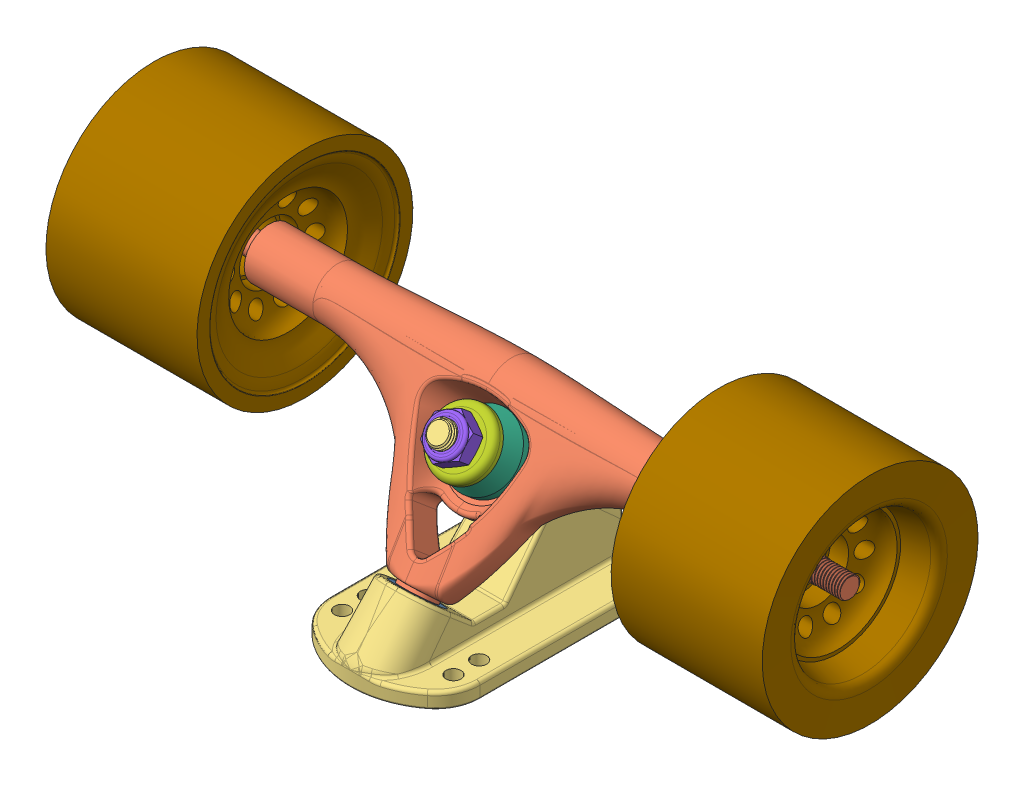
SolidWorks assembly Truck, configuration Default. Lengths in mm.
Overall size (265.5 107.22 102.66).
10 component instances, 9 part files, 22 mates.
Components (placement in the parent):
- Rubber Bushing-1: Rubber Bushing [Default] at (-27.686 9.105 71.5015) x (-0.125245 -0.637726 -0.760012) z (0 0.766044 -0.642788) size (17.78 17.78 15.24)
- Truck Black-1: Truck Black [Default] at (-27.686 18.8338 63.3381) x (1 0 0) z (0 -0.766044 0.642788) size (251.63 24.69 81.31)
- Truck Silver-1: Truck Silver [Default] at (-27.686 0 0) x (-1 0 0) z (0 0 -1) size (55.37 68.72 102.66)
- Large Washer-1: Large Washer [Default] at (-27.686 37.0748 22.445) x (1 0 0) z (0 -0.642788 -0.766044) size (29.97 29.97 4.65)
- Fat Bushing-1: Fat Bushing [Default] at (-27.686 38.3809 24.0016) x (0.983823 -0.137233 0.115152) z (-0.179144 -0.753652 0.632389) size (25.4 13.76 25.4)
- Small Bushing-1: Small Bushing [Default] at (-27.686 49.674 37.4601) x (0.221595 -0.747 0.626807) z (0 -0.642788 -0.766044) size (25.4 25.4 13.33)
- Small Washer-1: Small Washer [Default] at (-27.686 59.5517 49.2319) x (0.99468 -0.07891 0.066213) z (0 0.642788 0.766044) size (23.24 23.24 4.15)
- 3_8 nut-1: 3_8 nut [94945A218] at (-27.686 59.5517 49.2319) x (1 0 0) z (0 -0.766044 0.642788) size (14.29 7.02 16.5)
- Kegel 80mm longboard wheel-1: Kegel 80mm longboard wheel [Default] at (-123.0988 64.6541 29.035) x (0 -0.998139 0.06098) z (0 0.06098 0.998139) size (80 56 80)
- Kegel 80mm longboard wheel-2: Kegel 80mm longboard wheel [Default] at (67.7268 64.6541 29.035) x (0 -0.998139 0.06098) z (0 -0.06098 -0.998139) size (80 56 80)
Mates (geometry in assembly coordinates):
- Concentric1: concentric: cylinder of Rubber Bushing-1 through (-27.686 9.105 71.5015) axis (0 0.766044 -0.642788) radius 8.89; cylinder of Truck Silver-1 through (-27.686 6.1864 73.9505) axis (0 0.766044 -0.642788) radius 8.89
- Coincident1: coincident: plane of Rubber Bushing-1 through (-28.4972 13.7303 59.2319) normal (0 0.766044 -0.642788); plane of Truck Silver-1 through (-40.767 10.922 55.885) normal (0 0.766044 -0.642788)
- Concentric2: concentric: cylinder of Rubber Bushing-1 through (-27.686 9.105 71.5015) axis (0 0.766044 -0.642788) radius 6.477; cylinder of Truck Black-1 through (-27.686 9.105 71.5015) axis (0 0.766044 -0.642788) radius 6.477
- Coincident4: coincident: plane of Truck Silver-1 through (-27.686 0 0) normal (0 -1 0); plane of assembly through (0 0 0) normal (0 1 0)
- Coincident5: coincident: plane of Truck Silver-1 through (0 5.715 0) normal (1 0 0); plane of assembly through (0 0 0) normal (1 0 0)
- Coincident6: coincident: plane of Truck Silver-1 through (-27.686 5.715 0) normal (0 0 -1); plane of assembly through (0 0 0) normal (0 0 1)
- Concentric4: concentric: sphere of Rubber Bushing-1; sphere of Truck Black-1
- Parallel1: parallel: plane of Truck Black-1 through (97.7265 64.6541 29.035) normal (1 0 0); plane of Truck Silver-1 through (0 5.715 0) normal (1 0 0)
- Concentric5: concentric: cylinder of Truck Silver-1 through (-27.686 65.6467 56.4957) axis (0 -0.642788 -0.766044) radius 4.699; cylinder of Large Washer-1 through (-27.686 37.0748 22.445) axis (0 -0.642788 -0.766044) radius 4.7625
- Coincident8: coincident: plane of Truck Silver-1 through (-40.767 44.704 16.0434) normal (0 0.642788 0.766044); plane of Large Washer-1 through (-27.686 37.0748 22.445) normal (0 -0.642788 -0.766044)
- Concentric6: concentric: cylinder of Truck Silver-1 through (-27.686 65.6467 56.4957) axis (0 -0.642788 -0.766044) radius 4.699; cylinder of Fat Bushing-1 through (-27.686 47.2249 34.5415) axis (0 -0.642788 -0.766044) radius 4.7625
- Coincident9: coincident: plane of Large Washer-1 through (-27.686 38.3809 24.0016) normal (0 0.642788 0.766044); plane of Fat Bushing-1 through (-27.686 38.3809 24.0016) normal (0 -0.642788 -0.766044)
- Concentric7: concentric: cylinder of Truck Silver-1 through (-27.686 65.6467 56.4957) axis (0 -0.642788 -0.766044) radius 4.699; cylinder of Small Bushing-1 through (-27.686 49.674 37.4601) axis (0 -0.642788 -0.766044) radius 4.7625
- Coincident10: coincident: plane of Truck Black-1 through (-27.686 48.8957 38.1132) normal (0 0.642788 0.766044); plane of Small Bushing-1 through (-27.686 49.674 37.4601) normal (0 -0.642788 -0.766044)
- Concentric8: concentric: cylinder of Small Bushing-1 through (-27.686 49.674 37.4601) axis (0 -0.642788 -0.766044) radius 4.7625; cylinder of Small Washer-1 through (-27.686 59.5517 49.2319) axis (0 0.642788 0.766044) radius 4.7625
- Coincident11: coincident: plane of Small Bushing-1 through (-27.686 58.2455 47.6753) normal (0 0.642788 0.766044); plane of Small Washer-1 through (-27.686 58.2455 47.6753) normal (0 -0.642788 -0.766044)
- Concentric9: concentric: cylinder of Small Washer-1 through (-27.686 59.5517 49.2319) axis (0 0.642788 0.766044) radius 4.7625; cylinder of 3_8 nut-1 through (-27.686 63.2147 53.5973) axis (0 -0.642788 -0.766044) radius 4.2443
- Coincident12: coincident: plane of Small Washer-1 through (-27.686 59.5517 49.2319) normal (0 0.642788 0.766044); plane of 3_8 nut-1 through (-27.686 65.8707 43.9297) normal (0 -0.642788 -0.766044)
- Parallel2: parallel: plane of Truck Black-1 through (62.314 64.6541 29.035) normal (1 0 0); plane of 3_8 nut-1 through (-20.5423 60.729 57.0515) normal (1 0 0)
- Concentric10: concentric: cylinder of Truck Black-1 through (97.7265 64.6541 29.035) axis (-1 0 0) radius 4; cylinder of Kegel 80mm longboard wheel-1 through (-154.686 64.6541 29.035) axis (1 0 0) radius 9.75
- Concentric11: concentric: circle of Truck Black-1; circle of Kegel 80mm longboard wheel-1
- Coincident14: coincident: plane of Truck Black-1 through (-117.686 64.6541 29.035) normal (-1 0 0); circle of Kegel 80mm longboard wheel-1
